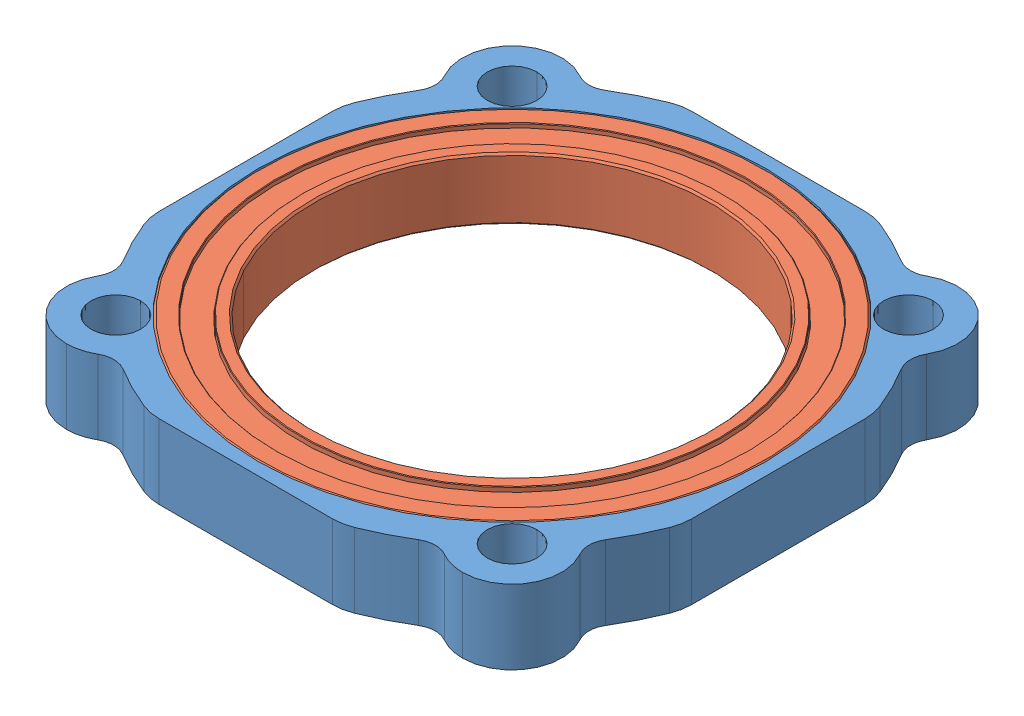
SolidWorks assembly 1603-0032-0032 assembly, configuration Default. Lengths in mm.
Overall size (55.53 6 55.53).
3 component instances, 2 part files, 0 mates.
Components (placement in the parent):
- 1603-0032-0032 assembly.STEP-1: 1603-0032-0032 assembly.STEP [Default] at origin size (55.53 6 55.53)
  - 1603-0032-0032.STEP-1: 1603-0032-0032.STEP [Default] at (-31.4475 11.5189 6.7305) size (43 6 43)
  - 1601-0039-00032.STEP-1: 1601-0039-00032.STEP [Default] at (-31.4475 15.0189 6.7305) x (0.473716 0 0.880678) z (-0.880678 0 0.473716) size (41 5 41)
